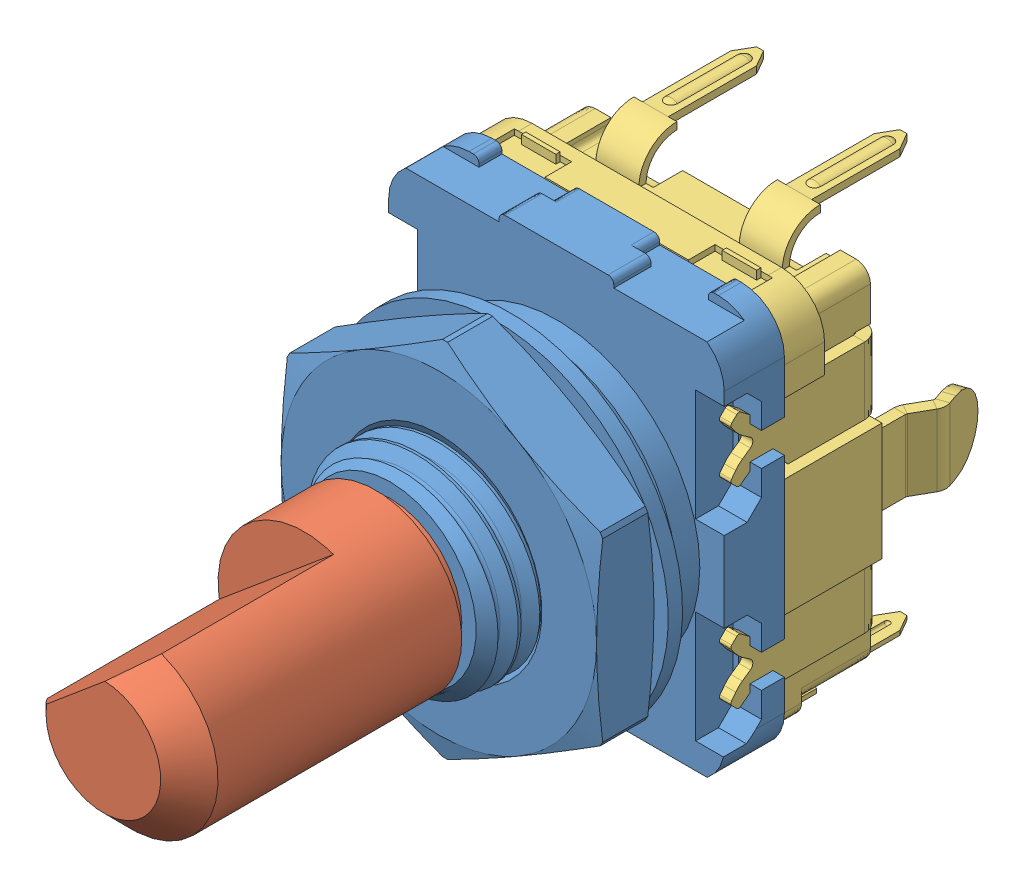
SolidWorks assembly EC11B-SW-Vert-15F-black, configuration Default. Lengths in mm.
Overall size (12 14.93 25.4).
4 component instances, 3 part files, 0 mates.
Components (placement in the parent):
- EC11B-SW-Vert-15F-black.step-1: EC11B-SW-Vert-15F-black.step [Default] at origin size (12 14.93 25.4)
  - eBom-prt0.step-1: eBom-prt0.step [Default] at (0 0 6.9) size (12 13.75 8.03)
  - eBom-prt1.step-1: eBom-prt1.step [Default] at (0 0 6.9) size (6 6 17.9)
  - eBom-prt2.step-1: eBom-prt2.step [Default] at (0 0 4) size (11.7 14.88 8.97)
